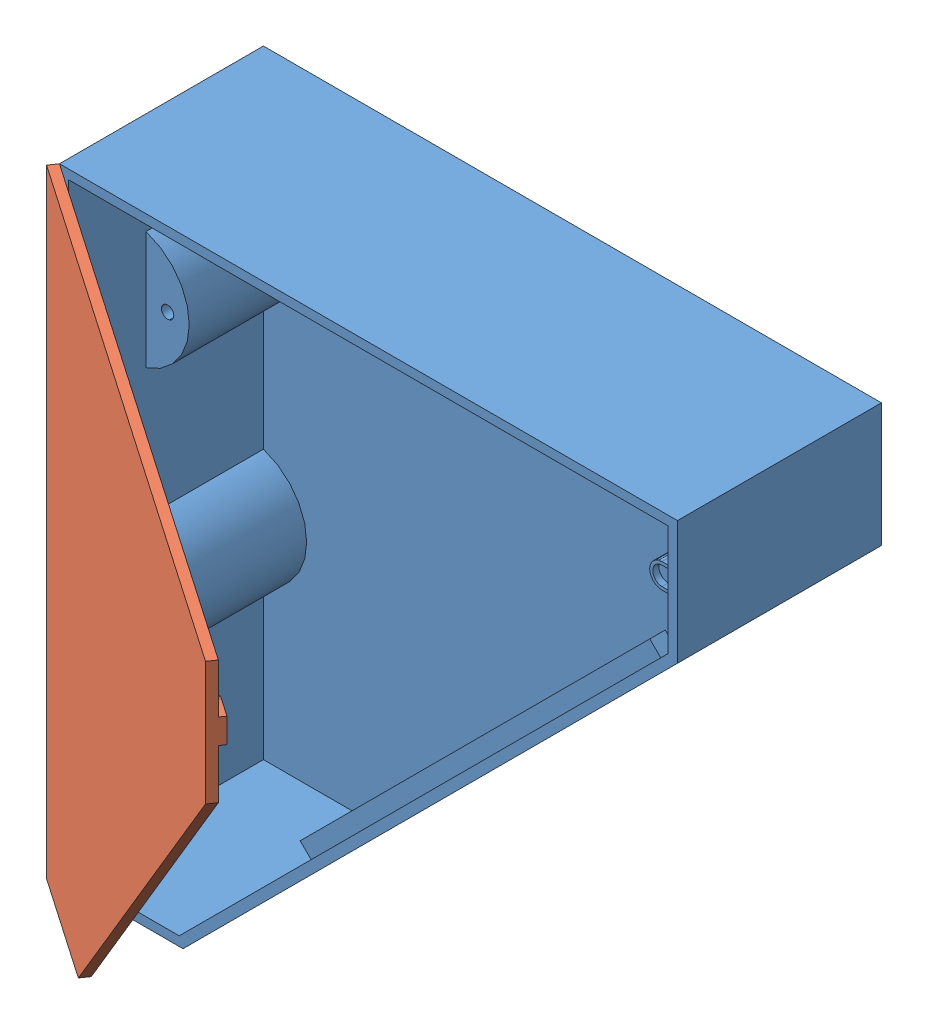
SolidWorks assembly prova1, configuration Default. Lengths in mm.
Overall size (201.7 200 198.83).
4 component instances, 4 part files, 5 mates.
Components (placement in the parent):
- base prova-1: base prova [Default] at origin size (200 200 66)
- Parte5^prova1-1: Parte5^prova1 [Default] at (0 0 -17) size (48 62 0) (virtual)
- layer2-1: layer2 [Default] at (3 6.4212 41) size (183 188 5) (hidden)
- lid prova-2: lid prova [Default] at (0 0 66) x (0.823876 0 0.566771) z (-0.566771 0 0.823876) size (200 200 5)
Mates (geometry in assembly coordinates):
- Coincidente7: coincident: plane of base prova-1 through (-3 70.9212 41) normal (0 0 1); line of layer2-1 through (186 156.7055 41) axis (0 1 0)
- Concentrico3: concentric aligned: cylinder of base prova-1 through (10 150.9212 11) axis (0 0 1) radius 2; cylinder of layer2-1 through (10 150.9212 46) axis (0 0 1) radius 4
- Concentrico4: concentric aligned: cylinder of base prova-1 through (10 70.9212 11) axis (0 0 1) radius 2; cylinder of layer2-1 through (10 70.9212 46) axis (0 0 1) radius 4
- Coincidente9: coincident anti-aligned: line of base prova-1 through (0 0 66) axis (0 1 0); line of lid prova-2 through (0 200 66) axis (0 -1 0)
- Coincidente10: coincident: point of base prova-1; point of lid prova-2
